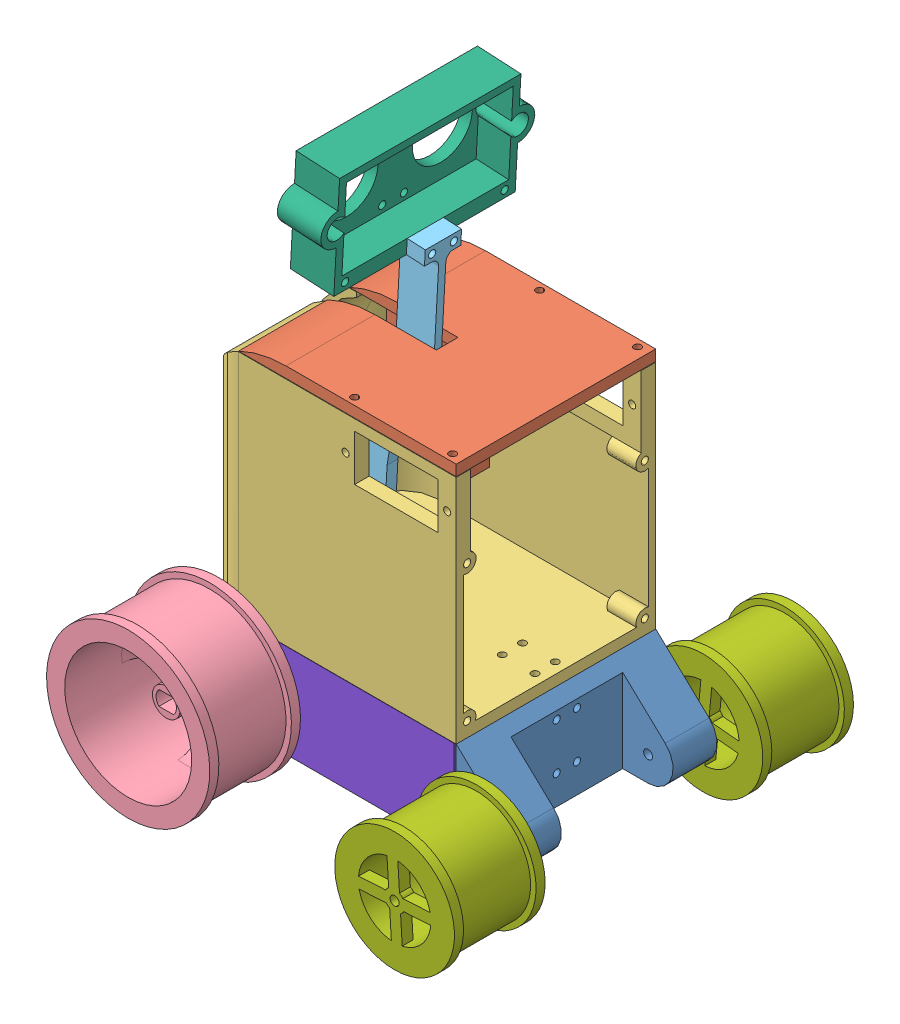
SolidWorks assembly Assem1, configuration Default. Lengths in mm.
Overall size (114 154 110).
10 component instances, 8 part files, 15 mates.
Components (placement in the parent):
- Part6-2: Part6 [Default] at (25.1793 24.1348 27.4082) size (16.9 25.8 55)
- Part3-1: Part3 [Default] at (25.1793 24.2847 27.4082) size (60 36.6 55)
- Part2-1: Part2 [Default] at (25.1793 24.1348 27.4082) size (70 64.9 55)
- tekerlek v3-1: tekerlek v3 [Default] at (-3.3405 34.9221 81.8301) x (0 0 1) z (0 -1 0) size (25 45 45)
- tekerlek v3-2: tekerlek v3 [Default] at (-0.7488 35.5348 27.9863) x (0 0 -1) z (-0.01976 0.999805 0) size (25 45 45)
- part4-1: part4 [Default] at (21.5859 97.7602 63.9082) x (-0.054846 -0.998495 0) z (0 0 -1) size (61.3 10.5 17)
- part5-1: part5 [Default] at (18.3106 101.9462 45.9082) x (-0.054846 -0.998495 0) z (0 0 1) size (29 12 59)
- tekerlek v4-1: tekerlek v4 [Default] at (70.1793 29.5348 136.8998) x (0 0 -1) z (-0.998114 -0.061384 0) size (25 33 33)
- Part1-3: Part1 [Default] at (24.5121 23.9739 27.3284) size (70 25.8 55)
- tekerlek v4-2: tekerlek v4 [Default] at (70.1793 29.5348 51.9022) x (0 0 -1) z (0.995546 -0.094282 0) size (25 33 33)
Mates (geometry in assembly coordinates):
- Coincident4: coincident aligned: plane of Part3-1 through (25.1793 24.2847 82.4082) normal (0 0 1); plane of Part2-1 through (25.1793 24.1348 82.4082) normal (0 0 1)
- Coincident5: coincident aligned: plane of Part3-1 through (60.1793 25.7847 82.4082) normal (1 0 0); plane of Part2-1 through (60.1793 25.6348 82.4082) normal (1 0 0)
- Coincident6: coincident: plane of Part6-2 through (60.1793 25.6348 82.4082) normal (1 0 0); plane of Part2-1 through (60.1793 25.6348 82.4082) normal (1 0 0)
- Coincident7: coincident aligned: plane of Part6-2 through (25.1793 24.1348 82.4082) normal (0 0 1); plane of Part2-1 through (25.1793 24.1348 82.4082) normal (0 0 1)
- Coincident8: coincident: plane of Part6-2 through (25.1793 48.4348 27.4082) normal (0 1 0); plane of Part2-1 through (25.1793 48.4348 27.4082) normal (0 -1 0)
- Distance1: distance = 0.5 mm: plane of Part6-2 through (1.1793 32.0348 16.4082) normal (0 1 0); plane of tekerlek v3-2 through (-3.1217 32.5348 27.4082) normal (0 -1 0)
- Coincident9: coincident: plane of Part6-2 through (25.1793 24.1348 27.4082) normal (0 0 -1); plane of tekerlek v3-2 through (-0.7488 35.5348 27.4082) normal (0 0 1)
- Coincident10: coincident: plane of Part6-2 through (25.1793 24.1348 82.4082) normal (0 0 1); plane of tekerlek v3-1 through (-3.3405 35.5348 82.4082) normal (0 0 -1)
- Distance2: distance = 0.5 mm: plane of tekerlek v3-1 through (-5.7134 32.5348 82.4082) normal (0 -1 0); plane of Part6-2 through (1.1793 32.0348 16.4082) normal (0 1 0)
- Distance3: distance = 2 mm anti-aligned: plane of part4-1 through (-7.9716 112.6538 55.9082) normal (0 0 1); plane of Part3-1 through (35.1793 127.9847 57.9082) normal (0 0 -1)
- Concentric3: concentric anti-aligned: cylinder of part4-1 through (24.0431 137.936 57.9082) axis (0.998495 -0.054846 0) radius 1; cylinder of part5-1 through (74.1273 135.1849 57.9082) axis (-0.998495 0.054846 0) radius 1
- Concentric4: concentric anti-aligned: cylinder of part4-1 through (24.0431 137.936 51.9082) axis (0.998495 -0.054846 0) radius 1; cylinder of part5-1 through (74.1273 135.1849 51.9082) axis (-0.998495 0.054846 0) radius 1
- Coincident11: coincident anti-aligned: plane of part4-1 through (21.8355 97.7465 63.9082) normal (-0.998495 0.054846 0); plane of part5-1 through (22.0549 101.7405 45.9082) normal (0.998495 -0.054846 0)
- Concentric5: concentric aligned: cylinder of Part6-2 through (70.1793 29.5348 -3.4341) axis (0 0 1) radius 1.25; cylinder of tekerlek v4-1 through (70.1793 29.5348 106.3998) axis (0 0 1) radius 1.25
- Concentric6: concentric aligned: cylinder of Part6-2 through (70.1793 29.5348 -3.4341) axis (0 0 1) radius 1.25; cylinder of tekerlek v4-2 through (70.1793 29.5348 21.4022) axis (0 0 1) radius 1.25
